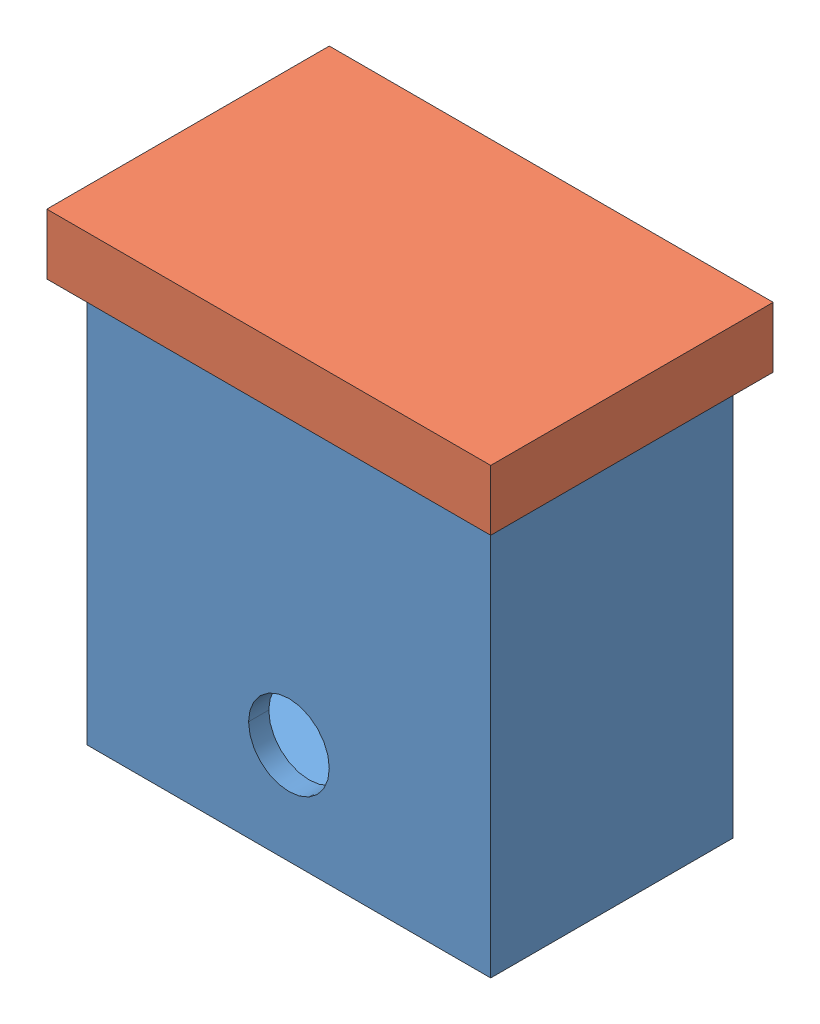
SolidWorks assembly RR-05-Reservior_Assem, configuration Default. Lengths in mm.
Overall size (220 230 140).
2 component instances, 2 part files, 5 mates.
Components (placement in the parent):
- RR-04-Reservoir2-1: RR-04-Reservoir2 [Default] at origin size (200 220 120)
- RR-04-Lid-1: RR-04-Lid [Default] at (207.6298 300.0463 126.0045) x (0 0 1) z (0 -1 0) size (140 220 30)
Mates (geometry in assembly coordinates):
- Coincident2: coordinate: point of RR-04-Reservoir2-1
- Parallel1: parallel: plane of RR-04-Reservoir2-1 through (0 0 0) normal (0 1 0); plane of RR-04-Lid-1 through (207.6298 363.8721 126.0045) normal (0 -1 0)
- Parallel2: parallel: plane of RR-04-Reservoir2-1 through (0 0 0) normal (1 0 0); plane of RR-04-Lid-1 through (207.6298 363.8721 126.0045) normal (-1 0 0)
- Coincident3: coincident: line of RR-04-Reservoir2-1 through (200 70.0463 120) axis (0 1 0); line of RR-04-Lid-1 through (200 353.8721 120) axis (0 -1 0)
- Coincident4: coincident anti-aligned: plane of RR-04-Reservoir2-1 through (0 290.0463 120) normal (0 1 0); plane of RR-04-Lid-1 through (207.6298 353.8721 126.0045) normal (0 -1 0)
